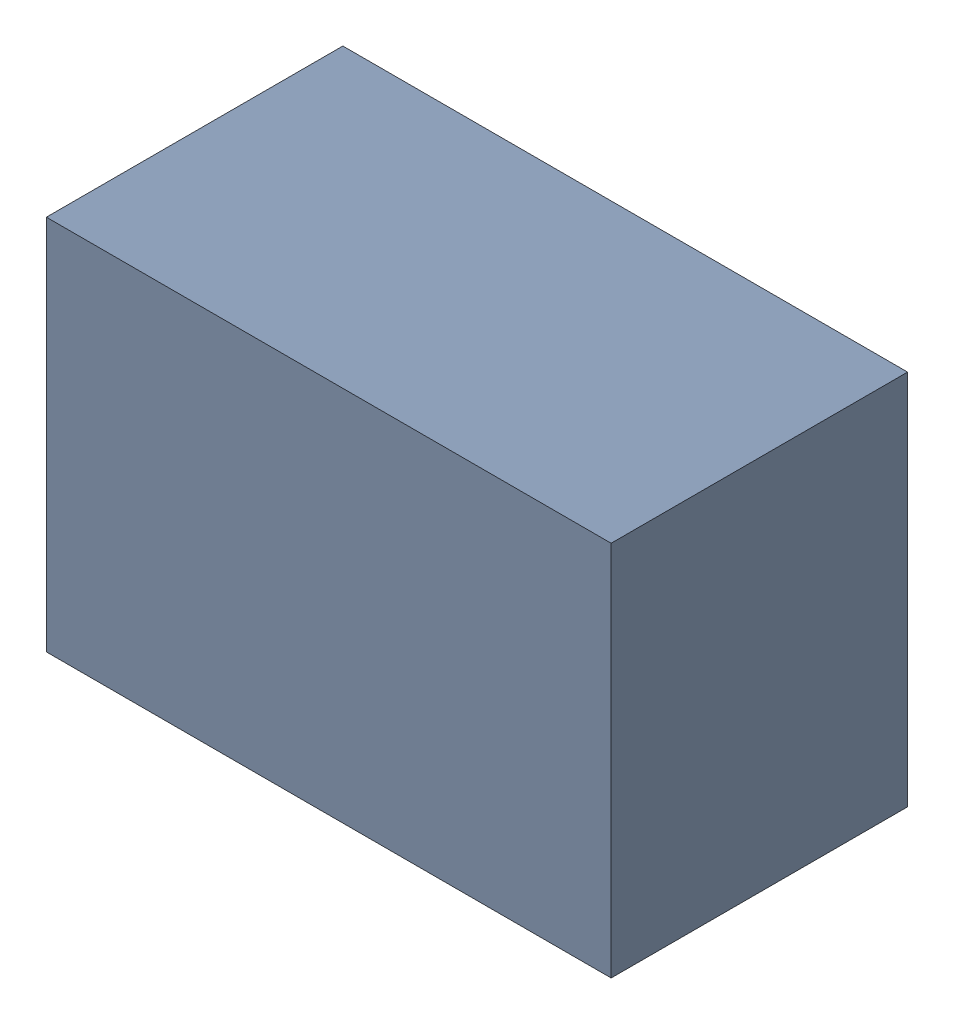
SolidWorks assembly USB67_L2, configuration Default. Lengths in mm.
Overall size (2.29 1.52 1.2).
2 component instances, 1 part files, 0 mates.
Components (placement in the parent):
- 402659088-1: 402659088 [Default] at (145.288 93.472 -2.3024) size (2.29 1.52 1.2)
  - Extruded_28-1: Extruded_28 [Default] at origin size (2.29 1.52 1.2)
